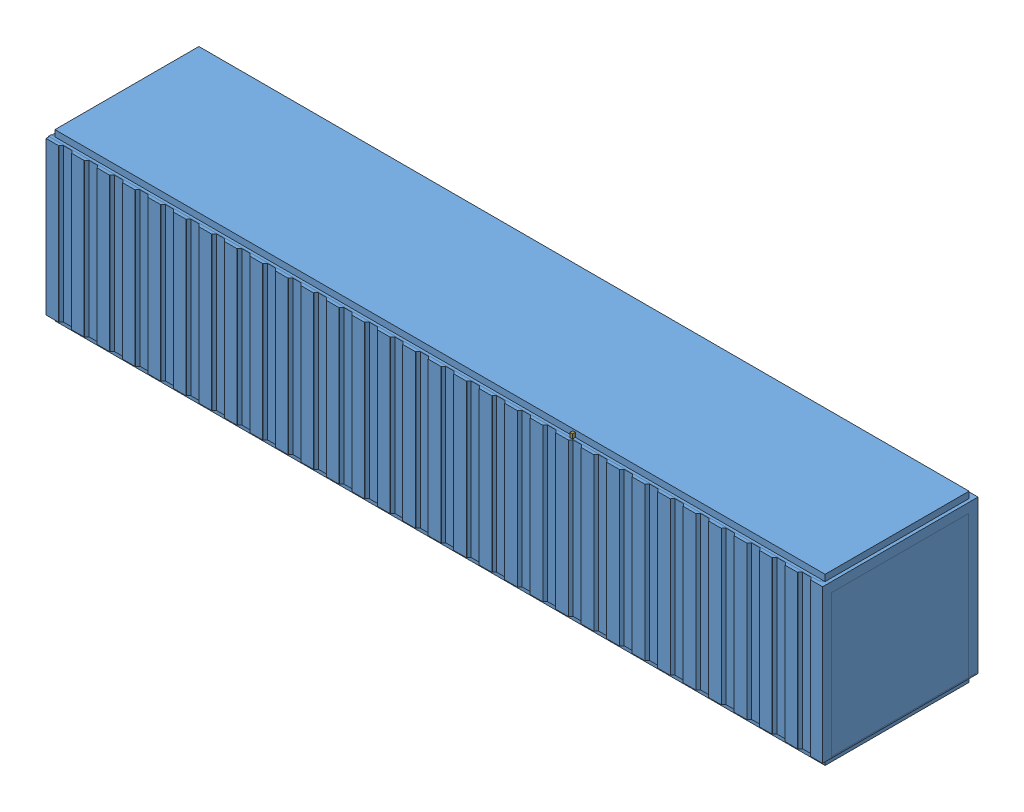
SolidWorks assembly BSL2-lab, configuration Default. Lengths in mm.
Overall size (14127.22 3869.25 2440).
96 component instances, 13 part files, 47 mates.
Components (placement in the parent):
- CONTAINERLIB02-1: CONTAINERLIB02 [Default] at (-5704.1486 155.7531 2904.1851) size (14127.22 3869.25 2440)
- tablfeformtable-1: tablfeformtable [Default] at (-1109.9755 1055.7531 1284.1851) size (1800 900 750)
- tablfeformtable-2: tablfeformtable [Default] at (2864.601 1055.7531 1284.1851) size (1800 900 750)
- tablfeformtable-3: tablfeformtable [Default] at (4654.2103 1055.7531 1284.1851) size (1800 900 750)
- tablfeformtable-4: tablfeformtable [Default] at (-4711.2144 1055.7531 1284.1851) size (1800 900 750)
- tablfeformtable-5: tablfeformtable [Default] at (-2910.8797 1055.7531 1284.1851) size (1800 900 750)
- tablfeformtable-6: tablfeformtable [Default] at (686.0662 1055.7531 1284.1851) size (1800 900 750)
- sink-1: sink [Default] at (-5575.7793 1075.7531 1159.1851) size (750 900 600)
- ot2-10: ot2 [Default] at (-945.412 1075.7531 1225.046) size (630 660 575)
- ot2-11: ot2 [Default] at (-144.2623 1075.7531 1225.046) size (630 660 575)
- ot2-12: ot2 [Default] at (897.9264 1075.7531 1225.046) size (630 660 575)
- ot2-13: ot2 [Default] at (1684.3216 1075.7531 1225.046) size (630 660 575)
- ot2-14: ot2 [Default] at (3837.1317 1075.7531 1225.046) size (630 660 575)
- pcr-5: pcr [Default] at (5391.4419 1075.7531 734.6241) x (0 0 1) z (-1 0 0) size (328.24 490.37 302.83)
- pcr-6: pcr [Default] at (5853.3864 1075.7531 735.2329) x (0 0 1) z (-1 0 0) size (328.24 490.37 302.83)
- bsl-2: bsl [Default] at (-4579.6999 1075.7531 1159.1851) size (1500 1200 600)
- drawers-1: drawers [Default] at (-2407.6331 398.0102 632.7319) size (620 892 450)
  - drawer-1: drawer [Default] at (-268.0912 -140.2571 236.7567) size (620 820 450)
  - rolls-1: rolls [Default] at (281.9088 -197.2571 621.7567) size (50 75 30)
  - rolls-2: rolls [Default] at (281.9088 -197.2571 271.7567) size (50 75 30)
  - rolls-3: rolls [Default] at (-238.0912 -197.2571 271.7567) size (50 75 30)
  - rolls-4: rolls [Default] at (-238.0912 -197.2571 621.7567) size (50 75 30)
  - box-1: box [Default] at (-268.0912 482.4435 646.2672) size (610 170 410)
  - box-2: box [Default] at (-268.0912 292.4435 644.3936) size (610 170 410)
  - box-3: box [Default] at (-268.0912 102.4435 642.5201) size (610 170 410)
  - box-4: box [Default] at (-268.0912 -87.5565 644.3936) size (610 170 410)
- drawers-2: drawers [Default] at (3218.8563 398.0102 622.4915) size (620 892 450)
  - drawer-1: drawer [Default] at (-268.0912 -140.2571 236.7567) size (620 820 450)
  - rolls-1: rolls [Default] at (281.9088 -197.2571 621.7567) size (50 75 30)
  - rolls-2: rolls [Default] at (281.9088 -197.2571 271.7567) size (50 75 30)
  - rolls-3: rolls [Default] at (-238.0912 -197.2571 271.7567) size (50 75 30)
  - rolls-4: rolls [Default] at (-238.0912 -197.2571 621.7567) size (50 75 30)
  - box-1: box [Default] at (-268.0912 482.4435 646.2672) size (610 170 410)
  - box-2: box [Default] at (-268.0912 292.4435 644.3936) size (610 170 410)
  - box-3: box [Default] at (-268.0912 102.4435 642.5201) size (610 170 410)
  - box-4: box [Default] at (-268.0912 -87.5565 644.3936) size (610 170 410)
- drawers-3: drawers [Default] at (-658.2825 398.0102 616.9053) size (620 892 450)
  - drawer-1: drawer [Default] at (-268.0912 -140.2571 236.7567) size (620 820 450)
  - rolls-1: rolls [Default] at (281.9088 -197.2571 621.7567) size (50 75 30)
  - rolls-2: rolls [Default] at (281.9088 -197.2571 271.7567) size (50 75 30)
  - rolls-3: rolls [Default] at (-238.0912 -197.2571 271.7567) size (50 75 30)
  - rolls-4: rolls [Default] at (-238.0912 -197.2571 621.7567) size (50 75 30)
  - box-1: box [Default] at (-268.0912 482.4435 646.2672) size (610 170 410)
  - box-2: box [Default] at (-268.0912 292.4435 644.3936) size (610 170 410)
  - box-3: box [Default] at (-268.0912 102.4435 642.5201) size (610 170 410)
  - box-4: box [Default] at (-268.0912 -87.5565 644.3936) size (610 170 410)
- Part11^labv02-1: Part11^labv02 [Default] at origin (virtual)
- large-1: large [Default] at (-4353.0866 373.514 2067.7937) size (620 1712 450.05)
  - drawer-1: drawer [Default] at (-420.3474 -102.4158 291.3914) size (620 820 450)
  - drawer-2: drawer [Default] at (-420.3474 717.5842 291.3914) size (620 820 450)
  - rolls-1: rolls [Default] at (129.6526 -159.4158 326.3914) size (50 75 30)
  - rolls-2: rolls [Default] at (-390.3474 -159.4158 676.3914) size (50 75 30)
  - rolls-3: rolls [Default] at (-390.3474 -159.4158 326.3914) size (50 75 30)
  - rolls-4: rolls [Default] at (129.6526 -159.4158 676.3914) size (50 75 30)
  - box-1: box [Default] at (-420.3474 1150.2849 696.345) size (610 170 410)
  - box-2: box [Default] at (-420.3474 960.2849 696.345) size (610 170 410)
  - box-3: box [Default] at (-420.3474 770.2849 698.2867) size (610 170 410)
  - box-4: box [Default] at (-425.2988 1340.2849 696.345) size (610 170 410)
  - box-5: box [Default] at (-420.3474 520.2849 719.9882) size (610 170 410)
  - box-6: box [Default] at (-420.3474 330.2849 696.844) size (610 170 410)
  - box-7: box [Default] at (-420.3474 140.2849 723.8694) size (610 170 410)
  - box-8: box [Default] at (-420.3474 -49.7151 730.5649) size (610 170 410)
- large-2: large [Default] at (373.1389 359.8445 2067.7937) size (620 1712 450.05)
  - drawer-1: drawer [Default] at (-420.3474 -102.4158 291.3914) size (620 820 450)
  - drawer-2: drawer [Default] at (-420.3474 717.5842 291.3914) size (620 820 450)
  - rolls-1: rolls [Default] at (129.6526 -159.4158 326.3914) size (50 75 30)
  - rolls-2: rolls [Default] at (-390.3474 -159.4158 676.3914) size (50 75 30)
  - rolls-3: rolls [Default] at (-390.3474 -159.4158 326.3914) size (50 75 30)
  - rolls-4: rolls [Default] at (129.6526 -159.4158 676.3914) size (50 75 30)
  - box-1: box [Default] at (-420.3474 1150.2849 696.345) size (610 170 410)
  - box-2: box [Default] at (-420.3474 960.2849 696.345) size (610 170 410)
  - box-3: box [Default] at (-420.3474 770.2849 698.2867) size (610 170 410)
  - box-4: box [Default] at (-425.2988 1340.2849 696.345) size (610 170 410)
  - box-5: box [Default] at (-420.3474 520.2849 719.9882) size (610 170 410)
  - box-6: box [Default] at (-420.3474 330.2849 696.844) size (610 170 410)
  - box-7: box [Default] at (-420.3474 140.2849 723.8694) size (610 170 410)
  - box-8: box [Default] at (-420.3474 -49.7151 730.5649) size (610 170 410)
- large-3: large [Default] at (4432.7363 370.4923 2067.7937) size (620 1712 450.05)
  - drawer-1: drawer [Default] at (-420.3474 -102.4158 291.3914) size (620 820 450)
  - drawer-2: drawer [Default] at (-420.3474 717.5842 291.3914) size (620 820 450)
  - rolls-1: rolls [Default] at (129.6526 -159.4158 326.3914) size (50 75 30)
  - rolls-2: rolls [Default] at (-390.3474 -159.4158 676.3914) size (50 75 30)
  - rolls-3: rolls [Default] at (-390.3474 -159.4158 326.3914) size (50 75 30)
  - rolls-4: rolls [Default] at (129.6526 -159.4158 676.3914) size (50 75 30)
  - box-1: box [Default] at (-420.3474 1150.2849 696.345) size (610 170 410)
  - box-2: box [Default] at (-420.3474 960.2849 696.345) size (610 170 410)
  - box-3: box [Default] at (-420.3474 770.2849 698.2867) size (610 170 410)
  - box-4: box [Default] at (-425.2988 1340.2849 696.345) size (610 170 410)
  - box-5: box [Default] at (-420.3474 520.2849 719.9882) size (610 170 410)
  - box-6: box [Default] at (-420.3474 330.2849 696.844) size (610 170 410)
  - box-7: box [Default] at (-420.3474 140.2849 723.8694) size (610 170 410)
  - box-8: box [Default] at (-420.3474 -49.7151 730.5649) size (610 170 410)
- locker-2: locker [Default] at (-4792.7958 175.7531 2809.1851) x (-1 0 0) z (0 0 -1) size (350 1800 500)
- fridgesmall-1: fridgesmall [Default] at (-1887.6212 175.7531 1159.1851) size (700 800 650)
- fridgesmall-2: fridgesmall [Default] at (3756.6553 175.7531 1159.1851) size (700 800 650)
- door-1: door [Default] at (2514.345 175.7531 559.1851) x (0 0 1) z (-1 0 0) size (2300 2450 40)
Mates (geometry in assembly coordinates):
- Coincident1: coincident anti-aligned: plane of CONTAINERLIB02-1 through (-5704.1486 175.7531 2904.1851) normal (0 1 0); plane of tablfeformtable-3 through (4654.2103 175.7531 1284.1851) normal (0 -1 0)
- Coincident2: coincident anti-aligned: plane of CONTAINERLIB02-1 through (-5704.1486 175.7531 2904.1851) normal (0 1 0); plane of tablfeformtable-2 through (2864.601 175.7531 1284.1851) normal (0 -1 0)
- Coincident3: coincident anti-aligned: plane of CONTAINERLIB02-1 through (-5704.1486 175.7531 2904.1851) normal (0 1 0); plane of tablfeformtable-1 through (-1109.9755 175.7531 1284.1851) normal (0 -1 0)
- Coincident4: coincident anti-aligned: plane of CONTAINERLIB02-1 through (-5704.1486 175.7531 2904.1851) normal (0 1 0); plane of tablfeformtable-4 through (-4711.2144 175.7531 1284.1851) normal (0 -1 0)
- Coincident5: coincident anti-aligned: plane of CONTAINERLIB02-1 through (-5704.1486 155.7531 559.1851) normal (0 0 1); plane of tablfeformtable-4 through (-4736.2144 1075.7531 559.1851) normal (0 0 -1)
- Coincident6: coincident anti-aligned: plane of CONTAINERLIB02-1 through (-5704.1486 155.7531 559.1851) normal (0 0 1); plane of tablfeformtable-1 through (-1134.9755 1075.7531 559.1851) normal (0 0 -1)
- Coincident7: coincident anti-aligned: plane of CONTAINERLIB02-1 through (-5704.1486 155.7531 559.1851) normal (0 0 1); plane of tablfeformtable-2 through (2839.601 1075.7531 559.1851) normal (0 0 -1)
- Coincident8: coincident anti-aligned: plane of CONTAINERLIB02-1 through (-5704.1486 155.7531 559.1851) normal (0 0 1); plane of tablfeformtable-3 through (4629.2103 1075.7531 559.1851) normal (0 0 -1)
- Coincident9: coincident anti-aligned: plane of CONTAINERLIB02-1 through (-5704.1486 175.7531 2904.1851) normal (0 1 0); plane of tablfeformtable-6 through (686.0662 175.7531 1284.1851) normal (0 -1 0)
- Coincident10: coincident anti-aligned: plane of CONTAINERLIB02-1 through (-5704.1486 155.7531 559.1851) normal (0 0 1); plane of tablfeformtable-6 through (661.0662 1075.7531 559.1851) normal (0 0 -1)
- Coincident11: coincident anti-aligned: plane of CONTAINERLIB02-1 through (-5704.1486 175.7531 2904.1851) normal (0 1 0); plane of sink-1 through (-4848.2793 175.7531 581.6851) normal (0 -1 0)
- Coincident12: coincident anti-aligned: plane of CONTAINERLIB02-1 through (-5704.1486 155.7531 559.1851) normal (0 0 1); plane of sink-1 through (-5575.7793 995.7531 559.1851) normal (0 0 -1)
- Coincident13: coincident anti-aligned: plane of CONTAINERLIB02-1 through (-5704.1486 175.7531 2904.1851) normal (0 1 0); plane of tablfeformtable-5 through (-2910.8797 175.7531 1284.1851) normal (0 -1 0)
- Coincident14: coincident anti-aligned: plane of CONTAINERLIB02-1 through (-5704.1486 155.7531 559.1851) normal (0 0 1); plane of tablfeformtable-5 through (-2935.8797 1075.7531 559.1851) normal (0 0 -1)
- Coincident15: coincident anti-aligned: plane of tablfeformtable-6 through (686.0662 1075.7531 1284.1851) normal (0 1 0); plane of ot2-14 through (3837.1317 1075.7531 1225.046) normal (0 -1 0)
- Coincident16: coincident anti-aligned: plane of tablfeformtable-4 through (-4711.2144 1075.7531 1284.1851) normal (0 1 0); plane of ot2-13 through (1684.3216 1075.7531 1225.046) normal (0 -1 0)
- Coincident17: coincident anti-aligned: plane of tablfeformtable-5 through (-2910.8797 1075.7531 1284.1851) normal (0 1 0); plane of ot2-12 through (897.9264 1075.7531 1225.046) normal (0 -1 0)
- Coincident18: coincident anti-aligned: plane of tablfeformtable-5 through (-2910.8797 1075.7531 1284.1851) normal (0 1 0); plane of ot2-11 through (-144.2623 1075.7531 1225.046) normal (0 -1 0)
- Coincident19: coincident anti-aligned: plane of tablfeformtable-1 through (-1109.9755 1075.7531 1284.1851) normal (0 1 0); plane of ot2-10 through (-945.412 1075.7531 1225.046) normal (0 -1 0)
- Coincident22: coincident aligned: plane of ot2-13 through (1684.3216 1735.7531 655.046) normal (0 0 -1); plane of ot2-14 through (3837.1317 1735.7531 655.046) normal (0 0 -1)
- Coincident23: coincident aligned: plane of ot2-12 through (897.9264 1735.7531 655.046) normal (0 0 -1); plane of ot2-13 through (1684.3216 1735.7531 655.046) normal (0 0 -1)
- Coincident24: coincident aligned: plane of ot2-11 through (-144.2623 1735.7531 655.046) normal (0 0 -1); plane of ot2-12 through (897.9264 1735.7531 655.046) normal (0 0 -1)
- Coincident25: coincident aligned: plane of ot2-10 through (-945.412 1735.7531 655.046) normal (0 0 -1); plane of ot2-11 through (-144.2623 1735.7531 655.046) normal (0 0 -1)
- Coincident28: coincident aligned: plane of pcr-5 through (5091.4419 1075.7531 734.6241) normal (0 -1 0); plane of pcr-6 through (5553.3864 1075.7531 735.2329) normal (0 -1 0)
- Coincident29: coincident anti-aligned: plane of tablfeformtable-3 through (4654.2103 1075.7531 1284.1851) normal (0 1 0); plane of pcr-5 through (5091.4419 1075.7531 734.6241) normal (0 -1 0)
- Coincident34: coincident anti-aligned: plane of CONTAINERLIB02-1 through (-5704.1486 155.7531 559.1851) normal (0 0 1); plane of bsl-2 through (-4579.6999 1025.7531 559.1851) normal (0 0 -1)
- Coincident35: coincident anti-aligned: plane of tablfeformtable-5 through (-2910.8797 1075.7531 1284.1851) normal (0 1 0); plane of bsl-2 through (-3079.6999 1075.7531 21159.1851) normal (0 -1 0)
- Tangent1: tangent anti-aligned: plane of CONTAINERLIB02-1 through (-5704.1486 175.7531 2904.1851) normal (0 1 0); cylinder of drawers-1/rolls-3 through (-2645.7244 200.7531 934.4887) axis (0 0 -1) radius 25
- Tangent2: tangent anti-aligned: plane of CONTAINERLIB02-1 through (-5704.1486 175.7531 2904.1851) normal (0 1 0); cylinder of drawers-1/rolls-1 through (-2125.7244 200.7531 1284.4887) axis (0 0 -1) radius 25
- Parallel2: parallel anti-aligned: plane of CONTAINERLIB02-1 through (-5704.1486 155.7531 559.1851) normal (0 0 1); plane of drawers-1/drawer-1 through (-2675.7244 257.7531 869.4887) normal (0 0 -1)
- Tangent3: tangent anti-aligned: plane of CONTAINERLIB02-1 through (-5704.1486 175.7531 2904.1851) normal (0 1 0); cylinder of drawers-2/rolls-4 through (2980.765 200.7531 1274.2482) axis (0 0 -1) radius 25
- Tangent4: tangent anti-aligned: plane of CONTAINERLIB02-1 through (-5704.1486 175.7531 2904.1851) normal (0 1 0); cylinder of drawers-2/rolls-2 through (3500.765 200.7531 924.2482) axis (0 0 -1) radius 25
- Parallel3: parallel anti-aligned: plane of CONTAINERLIB02-1 through (-5704.1486 155.7531 559.1851) normal (0 0 1); plane of drawers-2/drawer-1 through (2950.765 257.7531 859.2482) normal (0 0 -1)
- Parallel4: parallel anti-aligned: plane of CONTAINERLIB02-1 through (-5704.1486 155.7531 559.1851) normal (0 0 1); plane of drawers-3/drawer-1 through (-926.3737 257.7531 853.662) normal (0 0 -1)
- Tangent5: tangent anti-aligned: plane of CONTAINERLIB02-1 through (-5704.1486 175.7531 2904.1851) normal (0 1 0); cylinder of drawers-3/rolls-2 through (-376.3737 200.7531 918.662) axis (0 0 -1) radius 25
- Tangent6: tangent anti-aligned: plane of CONTAINERLIB02-1 through (-5704.1486 175.7531 2904.1851) normal (0 1 0); cylinder of drawers-3/rolls-3 through (-896.3737 200.7531 918.662) axis (0 0 -1) radius 25
- Coincident40: coincident anti-aligned: plane of CONTAINERLIB02-1 through (-5704.1486 155.7531 2809.1851) normal (0 0 -1); plane of large-1/drawer-1 through (-4773.434 271.0982 2809.1851) normal (0 0 1)
- Coincident41: coincident anti-aligned: plane of CONTAINERLIB02-1 through (-5704.1486 155.7531 2809.1851) normal (0 0 -1); plane of large-2/drawer-1 through (-47.2085 257.4287 2809.1851) normal (0 0 1)
- Coincident42: coincident anti-aligned: plane of CONTAINERLIB02-1 through (-5704.1486 155.7531 2809.1851) normal (0 0 -1); plane of large-3/drawer-2 through (4012.3888 1088.0765 2809.1851) normal (0 0 1)
- Coincident44: coincident anti-aligned: plane of CONTAINERLIB02-1 through (-5704.1486 155.7531 2809.1851) normal (0 0 -1); plane of locker-2 through (-4792.7958 175.7531 2809.1851) normal (0 0 1)
- Coincident45: coincident anti-aligned: plane of CONTAINERLIB02-1 through (-5704.1486 175.7531 2904.1851) normal (0 1 0); plane of locker-2 through (-4792.7958 175.7531 2309.1851) normal (0 -1 0)
- Coincident46: coincident anti-aligned: plane of CONTAINERLIB02-1 through (-5704.1486 175.7531 2904.1851) normal (0 1 0); plane of fridgesmall-2 through (3756.6553 175.7531 1159.1851) normal (0 -1 0)
- Coincident47: coincident aligned: plane of fridgesmall-1 through (-1887.6212 175.7531 1159.1851) normal (0 -1 0); plane of fridgesmall-2 through (3756.6553 175.7531 1159.1851) normal (0 -1 0)
- Coincident48: coincident anti-aligned: plane of CONTAINERLIB02-1 through (-5704.1486 155.7531 559.1851) normal (0 0 1); plane of fridgesmall-1 through (-1887.6212 975.7531 559.1851) normal (0 0 -1)
- Coincident49: coincident anti-aligned: plane of CONTAINERLIB02-1 through (-5704.1486 155.7531 559.1851) normal (0 0 1); plane of fridgesmall-2 through (3756.6553 975.7531 559.1851) normal (0 0 -1)
- Coincident50: coincident anti-aligned: plane of CONTAINERLIB02-1 through (-5704.1486 175.7531 2904.1851) normal (0 1 0); plane of door-1 through (2474.345 175.7531 559.1851) normal (0 -1 0)
- Coincident51: coincident anti-aligned: plane of CONTAINERLIB02-1 through (-5704.1486 155.7531 559.1851) normal (0 0 1); plane of door-1 through (2474.345 175.7531 559.1851) normal (0 0 -1)
